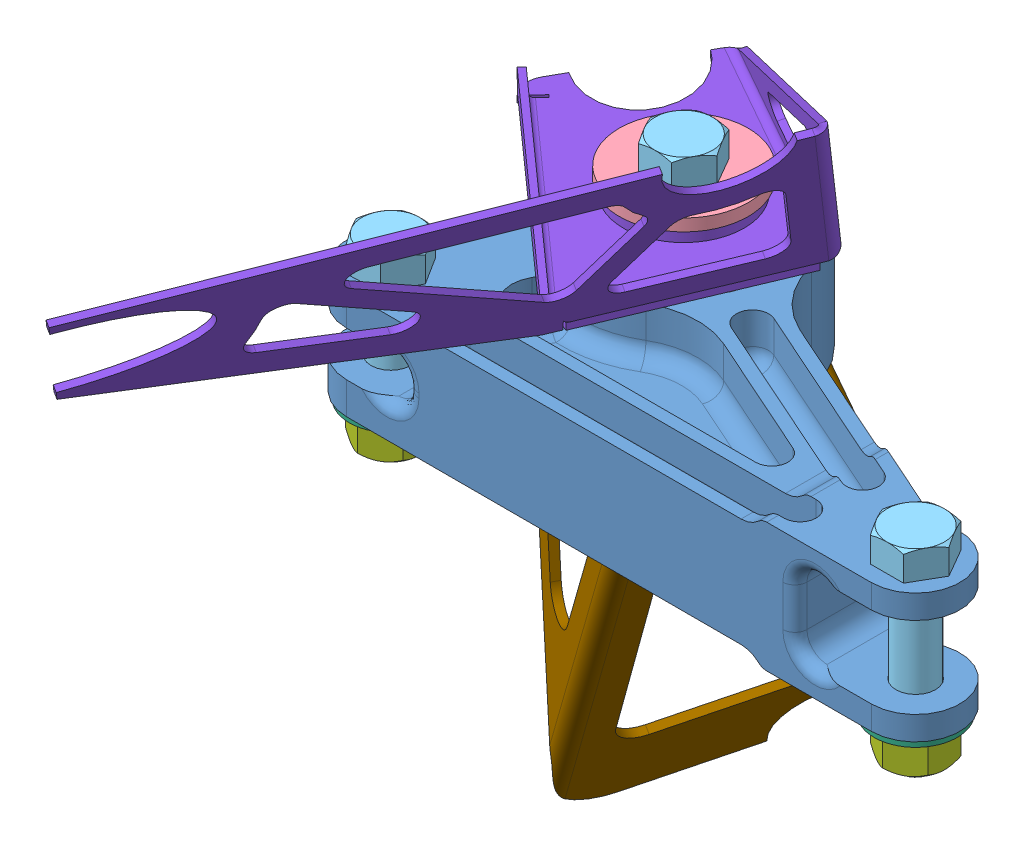
SolidWorks assembly SuspRockerFront2, configuration Default. Lengths in mm.
Overall size (230.54 235.57 222.32).
16 component instances, 9 part files, 35 mates.
Components (placement in the parent):
- SuspensionRockerFront-1: SuspensionRockerFront [Default] at (-167.704 -374.5553 271.4977) x (0.799673 -0.479372 0.36156) z (-0.485715 -0.162447 0.85889) size (146.88 97.9 105.29)
- BearingBall6005-1: BearingBall6005 [Default] at (0 7.5 0) size (47 12 47)
- BearingBall6005-2: BearingBall6005 [Default] at (0 -7.5 0) size (47 12 47)
- RockerArmShaft-2: RockerArmShaft [Front] x (0 -1 0) z (0.321816 0 0.946802) size (44.2 25 25)
- RockerArmShaftWasher-3: RockerArmShaftWasher [Default] at (0 25.1 0) x (1 0 0) z (0 -1 0) size (32 32 3)
- RockerArmShaftWasher-4: RockerArmShaftWasher [Default] at (0 -22.1 0) x (1 0 0) z (0 -1 0) size (32 32 3)
- Hex Bolt_AI-1: Hex Bolt_AI [HBOLT 0.3750-24x0.5x0.5-N] at (0 31.9072 0) x (0 -1 0) z (0 0 1) size (19.51 16.48 14.27)
- Hex Bolt_AI-2: Hex Bolt_AI [HBOLT 0.3750-24x0.5x0.5-N] at (0 -31.9072 0) x (0 1 0) z (0 0 1) size (19.51 16.48 14.27)
- Hex Bolt_AI-3: Hex Bolt_AI [HBOLT 0.3750-24x1.5x1-N] at (-26.4184 20.3072 46.3094) x (0 -1 0) z (0.041526 0 0.999137) size (44.91 16.48 14.27)
- Hex Bolt_AI-4: Hex Bolt_AI [HBOLT 0.3750-24x1.75x1-N] at (103.8966 22.8072 46.3094) x (0 -1 0) z (0 0 1) size (51.26 16.48 14.27)
- Flat Washer Type A Narrow_AI-1: Flat Washer Type A Narrow_AI [Preferred Narrow FW 0.375] at (-26.4184 -13.5 46.3094) x (0 1 0) z (0 0 1) size (1.65 20.62 20.62)
- Flat Washer Type A Narrow_AI-2: Flat Washer Type A Narrow_AI [Preferred Narrow FW 0.375] at (103.8966 -16 46.3094) x (0 1 0) z (0 0 1) size (1.65 20.62 20.62)
- Hex Nut_AI-1: Hex Nut_AI [HNUT 0.3750-24-D-N] at (-26.4184 -23.7108 46.3094) x (1 0 0) z (0 -1 0) size (14.27 16.48 8.56)
- Hex Nut_AI-2: Hex Nut_AI [HNUT 0.3750-24-D-N] at (103.8966 -26.2108 46.3094) x (1 0 0) z (0 -1 0) size (14.27 16.48 8.56)
- SuspensionRockerMountLeftFrontUpper-2: SuspensionRockerMountLeftFrontUpper [Finished Part<As Machined>] at (-75.4065 -468.7182 -79.9614) x (-0.481035 -0.208508 0.851546) z (-0.809267 0.479173 -0.339822) size (144.53 119.55 62.99)
- SuspensionRockerMountLeftFrontLower-1: SuspensionRockerMountLeftFrontLower [Finished Part<As Machined>] at (-75.4065 -468.7182 -79.9614) x (-0.481035 -0.208508 0.851546) z (-0.809267 0.479173 -0.339822) size (67.94 105.34 93.34)
Mates (geometry in assembly coordinates):
- Parallel1: parallel: plane of assembly through (0 0 0) normal (0 1 0); plane of SuspensionRockerFront-1 through (71.5466 13.5 -45.7435) normal (0 1 0); plane of assembly
- Parallel2: parallel: plane of assembly through (0 0 0) normal (0 0 1); plane of assembly; plane of SuspensionRockerFront-1 through (103.8966 -16 57.3094) normal (0 0 1)
- Coincident3: coincident: point of assembly; point of SuspensionRockerFront-1; point of assembly
- Concentric1: concentric: cylinder of assembly; cylinder of assembly; cylinder of SuspensionRockerFront-1 through (0 -16 0) axis (0 1 0) radius 23.5; cylinder of BearingBall6005-1 through (0 34.1807 0) axis (0 1 0) radius 23.5
- Coincident4: coincident: plane of assembly; plane of assembly; plane of SuspensionRockerFront-1 through (0 1.5 0) normal (0 1 0); plane of BearingBall6005-1 through (0 1.5 22.9) normal (0 -1 0)
- Concentric2: concentric: cylinder of assembly; cylinder of assembly; cylinder of SuspensionRockerFront-1 through (0 -16 0) axis (0 1 0) radius 23.5; cylinder of BearingBall6005-2 through (0 19.1807 0) axis (0 1 0) radius 23.5
- Coincident5: coincident: plane of assembly; plane of assembly; plane of SuspensionRockerFront-1 through (0 -1.5 0) normal (0 -1 0); plane of BearingBall6005-2 through (0 -1.5 22.9) normal (0 1 0)
- Concentric3: concentric: cylinder of assembly; cylinder of assembly; cylinder of BearingBall6005-1 through (0 34.1807 0) axis (0 1 0) radius 12.5; cylinder of RockerArmShaft-2 through (0 22.1 0) axis (0 -1 0) radius 12.5
- Coincident6: coincident: plane of assembly; plane of assembly; plane of SuspensionRockerFront-1 through (-167.704 0 271.4977) normal (0 1 0); plane of RockerArmShaft-2 through (0 0 0) normal (0 -1 0)
- Concentric6: concentric: cylinder of assembly; cylinder of assembly; cylinder of RockerArmShaft-2 through (0 22.1 0) axis (0 -1 0) radius 4.4196; cylinder of RockerArmShaftWasher-3 through (0 22.1 0) axis (0 1 0) radius 5
- Coincident10: coincident: plane of assembly; plane of assembly; plane of RockerArmShaft-2 through (0 22.1 0) normal (0 1 0); plane of RockerArmShaftWasher-3 through (0 22.1 0) normal (0 -1 0)
- Concentric7: concentric: cylinder of assembly; cylinder of assembly; cylinder of RockerArmShaft-2 through (0 22.1 0) axis (0 -1 0) radius 4.4196; cylinder of RockerArmShaftWasher-4 through (0 -25.1 0) axis (0 1 0) radius 5
- Coincident11: coincident: plane of assembly; plane of assembly; plane of RockerArmShaft-2 through (0 -22.1 0) normal (0 -1 0); plane of RockerArmShaftWasher-4 through (0 -22.1 0) normal (0 1 0)
- Concentric8: concentric: cylinder of assembly; cylinder of assembly; cylinder of RockerArmShaftWasher-3 through (0 22.1 0) axis (0 1 0) radius 5; cylinder of Hex Bolt_AI-1 through (0 31.9072 0) axis (0 1 0) radius 4.7625
- Coincident12: coincident: plane of assembly; plane of assembly; plane of RockerArmShaftWasher-3 through (0 25.1 0) normal (0 1 0); plane of Hex Bolt_AI-1 through (8.2416 25.1 0) normal (0 -1 0)
- Concentric9: concentric: cylinder of assembly; cylinder of assembly; cylinder of RockerArmShaftWasher-4 through (0 -25.1 0) axis (0 1 0) radius 5; cylinder of Hex Bolt_AI-2 through (0 -31.9072 0) axis (0 -1 0) radius 4.7625
- Coincident13: coincident: plane of assembly; plane of assembly; plane of RockerArmShaftWasher-4 through (0 -25.1 0) normal (0 -1 0); plane of Hex Bolt_AI-2 through (-8.2416 -25.1 0) normal (0 1 0)
- Concentric10: concentric: cylinder of assembly; cylinder of assembly; cylinder of SuspensionRockerFront-1 through (-26.4184 -16 46.3094) axis (0 1 0) radius 4.9022; cylinder of Hex Bolt_AI-3 through (-26.4184 20.3072 46.3094) axis (0 1 0) radius 4.7625
- Coincident14: coincident: plane of assembly; plane of assembly; plane of SuspensionRockerFront-1 through (71.5466 13.5 -45.7435) normal (0 1 0); plane of Hex Bolt_AI-3 through (-18.184 13.5 45.9671) normal (0 -1 0)
- Concentric11: concentric: cylinder of assembly; cylinder of assembly; cylinder of SuspensionRockerFront-1 through (103.8966 -16 46.3094) axis (0 1 0) radius 4.9022; cylinder of Hex Bolt_AI-4 through (103.8966 22.8072 46.3094) axis (0 1 0) radius 4.7625
- Coincident15: coincident: plane of assembly; plane of assembly; plane of SuspensionRockerFront-1 through (-28.9154 16 30.5054) normal (0 1 0); plane of Hex Bolt_AI-4 through (112.1382 16 46.3094) normal (0 -1 0)
- Concentric12: concentric: cylinder of assembly; cylinder of assembly; cylinder of Hex Bolt_AI-3 through (-26.4184 20.3072 46.3094) axis (0 1 0) radius 4.7625; cylinder of Flat Washer Type A Narrow_AI-1 through (-26.4184 -48.425 46.3094) axis (0 -1 0) radius 5.1562
- Coincident16: coincident: plane of assembly; plane of assembly; plane of SuspensionRockerFront-1 through (71.5466 -13.5 -45.7435) normal (0 -1 0); plane of Flat Washer Type A Narrow_AI-1 through (-31.5746 -13.5 46.3094) normal (0 1 0)
- Concentric13: concentric: cylinder of assembly; cylinder of assembly; cylinder of Hex Bolt_AI-4 through (103.8966 22.8072 46.3094) axis (0 1 0) radius 4.7625; cylinder of Flat Washer Type A Narrow_AI-2 through (103.8966 -50.925 46.3094) axis (0 -1 0) radius 5.1562
- Coincident17: coincident: plane of assembly; plane of assembly; plane of SuspensionRockerFront-1 through (-28.9154 -16 30.5054) normal (0 -1 0); plane of Flat Washer Type A Narrow_AI-2 through (98.7404 -16 46.3094) normal (0 1 0)
- Concentric14: concentric: cylinder of assembly; cylinder of assembly; cylinder of Hex Bolt_AI-3 through (-26.4184 20.3072 46.3094) axis (0 1 0) radius 4.7625; cylinder of Hex Nut_AI-1 through (-26.4184 1.3267 46.3094) axis (0 -1 0) radius 4.7625
- Coincident18: coincident: plane of assembly; plane of assembly; plane of Flat Washer Type A Narrow_AI-1 through (-36.7308 -15.151 46.3094) normal (0 -1 0); plane of Hex Nut_AI-1 through (-40.6932 -15.151 46.3094) normal (0 1 0)
- Concentric15: concentric: cylinder of assembly; cylinder of assembly; cylinder of Hex Bolt_AI-4 through (103.8966 22.8072 46.3094) axis (0 1 0) radius 4.7625; cylinder of Hex Nut_AI-2 through (103.8966 -1.1733 46.3094) axis (0 -1 0) radius 4.7625
- Coincident19: coincident: plane of assembly; plane of assembly; plane of Flat Washer Type A Narrow_AI-2 through (93.5842 -17.651 46.3094) normal (0 -1 0); plane of Hex Nut_AI-2 through (89.6218 -17.651 46.3094) normal (0 1 0)
- Concentric17: concentric: cylinder of RockerArmShaft-2 through (0 22.1 0) axis (0 -1 0) radius 12.5; cylinder of ? through (0 -22.1 0) axis (0 1 0) radius 12.5
- Angle1: planar angle = 0.230209 rad: plane of SuspensionRockerFront-1 through (97.0801 -16 35.6072) normal (0.407115 0 -0.913377); plane of ? through (17.1538 -99.1925 -39.4674) normal (0.481035 0.208508 -0.851546)
- Coincident27: coincident: plane of BearingBall6005-2 through (0 -13.5 16) normal (0 -1 0); plane of ? through (0 -13.5 0) normal (0 1 0)
- Concentric18: concentric: cylinder of RockerArmShaft-2 through (0 22.1 0) axis (0 -1 0) radius 12.5; cylinder of ? through (0 22.1 0) axis (0 -1 0) radius 12.5
- Coincident28: coincident: plane of BearingBall6005-1 through (0 13.5 16) normal (0 1 0); plane of ? through (0 13.5 0) normal (0 -1 0)
- Parallel3: parallel: line of ? through (-21.5107 21.3672 -37.2224) axis (0.870683 0 0.491845); line of ? through (-41.5177 -20.3494 -53.3054) axis (0.870683 0 0.491845)
